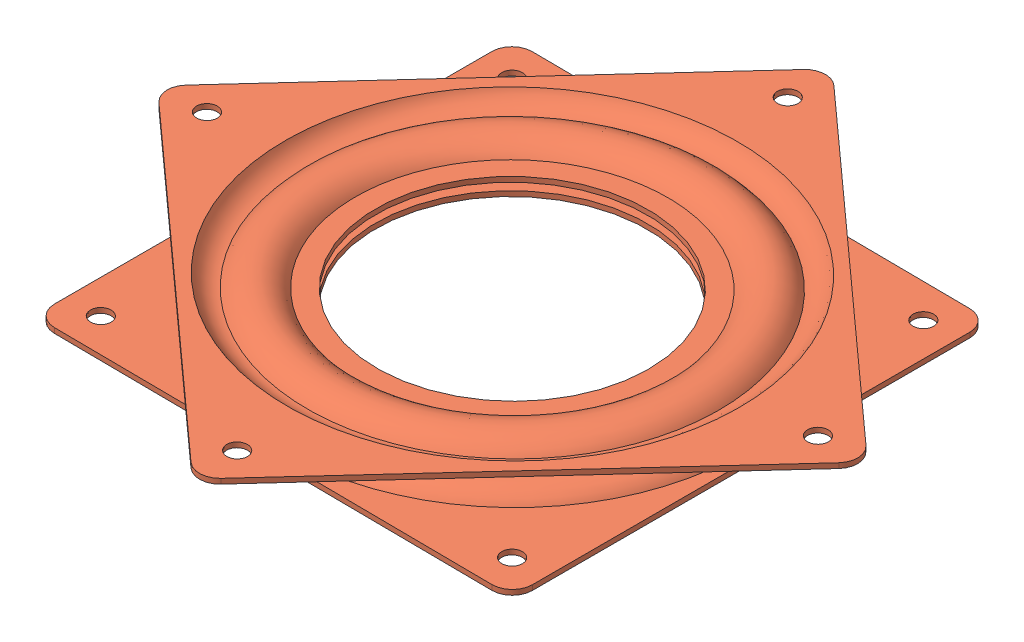
SolidWorks assembly 装配体1, configuration 默认. Lengths in mm.
Overall size (133.49 10.01 133.46).
32 component instances, 2 part files, 4 mates.
Components (placement in the parent):
- 6mmBearing-1: 6mmBearing [默认] at (34.5725 -23.9842 -78.8885) x (0.09369 0.188381 -0.977617) z (0.583167 0.785472 0.207244) size (6 6 6)
- HalfLazySusan-1: HalfLazySusan [默认] at (35.0426 -28.3053 -41.4748) x (-0.999962 0.008727 0) z (0 0 1) size (94.5 3.57 94.5)
- HalfLazySusan-2: HalfLazySusan [默认] at (35.1177 -19.7056 -41.4748) x (0.742856 -0.006483 0.669419) z (-0.669394 0.005842 0.742885) size (94.5 3.57 94.5)
- 6mmBearing-2: 6mmBearing [默认] at (42.067 -24.0496 -78.2035) x (0.09369 0.188381 -0.977617) z (0.583167 0.785472 0.207244) size (6 6 6)
- 6mmBearing-3: 6mmBearing [默认] at (49.2553 -24.1124 -75.9752) x (0.09369 0.188381 -0.977617) z (0.583167 0.785472 0.207244) size (6 6 6)
- 6mmBearing-4: 6mmBearing [默认] at (55.8233 -24.1697 -72.301) x (0.09369 0.188381 -0.977617) z (0.583167 0.785472 0.207244) size (6 6 6)
- 6mmBearing-5: 6mmBearing [默认] at (61.4839 -24.2191 -67.3414) x (0.09369 0.188381 -0.977617) z (0.583167 0.785472 0.207244) size (6 6 6)
- 6mmBearing-6: 6mmBearing [默认] at (65.9896 -24.2584 -61.3133) x (0.09369 0.188381 -0.977617) z (0.583167 0.785472 0.207244) size (6 6 6)
- 6mmBearing-7: 6mmBearing [默认] at (69.1437 -24.2859 -54.4801) x (0.09369 0.188381 -0.977617) z (0.583167 0.785472 0.207244) size (6 6 6)
- 6mmBearing-8: 6mmBearing [默认] at (70.8081 -24.3004 -47.1404) x (0.09369 0.188381 -0.977617) z (0.583167 0.785472 0.207244) size (6 6 6)
- 6mmBearing-9: 6mmBearing [默认] at (70.9103 -24.3013 -39.6151) x (0.09369 0.188381 -0.977617) z (0.583167 0.785472 0.207244) size (6 6 6)
- 6mmBearing-10: 6mmBearing [默认] at (69.4456 -24.2886 -32.2329) x (0.09369 0.188381 -0.977617) z (0.583167 0.785472 0.207244) size (6 6 6)
- 6mmBearing-11: 6mmBearing [默认] at (66.4782 -24.2627 -25.3166) x (0.09369 0.188381 -0.977617) z (0.583167 0.785472 0.207244) size (6 6 6)
- 6mmBearing-12: 6mmBearing [默认] at (62.1377 -24.2248 -19.1684) x (0.09369 0.188381 -0.977617) z (0.583167 0.785472 0.207244) size (6 6 6)
- 6mmBearing-13: 6mmBearing [默认] at (56.6138 -24.1766 -14.0571) x (0.09369 0.188381 -0.977617) z (0.583167 0.785472 0.207244) size (6 6 6)
- 6mmBearing-14: 6mmBearing [默认] at (50.148 -24.1201 -10.206) x (0.09369 0.188381 -0.977617) z (0.583167 0.785472 0.207244) size (6 6 6)
- 6mmBearing-15: 6mmBearing [默认] at (43.0228 -24.058 -7.7834) x (0.09369 0.188381 -0.977617) z (0.583167 0.785472 0.207244) size (6 6 6)
- 6mmBearing-16: 6mmBearing [默认] at (35.5496 -23.9927 -6.8952) x (0.09369 0.188381 -0.977617) z (0.583167 0.785472 0.207244) size (6 6 6)
- 6mmBearing-17: 6mmBearing [默认] at (28.0551 -23.9273 -7.5802) x (0.09369 0.188381 -0.977617) z (0.583167 0.785472 0.207244) size (6 6 6)
- 6mmBearing-18: 6mmBearing [默认] at (20.8668 -23.8646 -9.8085) x (0.09369 0.188381 -0.977617) z (0.583167 0.785472 0.207244) size (6 6 6)
- 6mmBearing-19: 6mmBearing [默认] at (14.2988 -23.8073 -13.4827) x (0.09369 0.188381 -0.977617) z (0.583167 0.785472 0.207244) size (6 6 6)
- 6mmBearing-20: 6mmBearing [默认] at (8.6382 -23.7579 -18.4423) x (0.09369 0.188381 -0.977617) z (0.583167 0.785472 0.207244) size (6 6 6)
- 6mmBearing-21: 6mmBearing [默认] at (4.1325 -23.7186 -24.4704) x (0.09369 0.188381 -0.977617) z (0.583167 0.785472 0.207244) size (6 6 6)
- 6mmBearing-22: 6mmBearing [默认] at (0.9785 -23.691 -31.3036) x (0.09369 0.188381 -0.977617) z (0.583167 0.785472 0.207244) size (6 6 6)
- 6mmBearing-23: 6mmBearing [默认] at (-0.686 -23.6765 -38.6432) x (0.09369 0.188381 -0.977617) z (0.583167 0.785472 0.207244) size (6 6 6)
- 6mmBearing-24: 6mmBearing [默认] at (-0.7881 -23.6756 -46.1686) x (0.09369 0.188381 -0.977617) z (0.583167 0.785472 0.207244) size (6 6 6)
- 6mmBearing-25: 6mmBearing [默认] at (0.6765 -23.6884 -53.5507) x (0.09369 0.188381 -0.977617) z (0.583167 0.785472 0.207244) size (6 6 6)
- 6mmBearing-26: 6mmBearing [默认] at (3.6439 -23.7143 -60.467) x (0.09369 0.188381 -0.977617) z (0.583167 0.785472 0.207244) size (6 6 6)
- 6mmBearing-27: 6mmBearing [默认] at (7.9844 -23.7522 -66.6152) x (0.09369 0.188381 -0.977617) z (0.583167 0.785472 0.207244) size (6 6 6)
- 6mmBearing-28: 6mmBearing [默认] at (13.5083 -23.8004 -71.7266) x (0.09369 0.188381 -0.977617) z (0.583167 0.785472 0.207244) size (6 6 6)
- 6mmBearing-29: 6mmBearing [默认] at (19.9741 -23.8568 -75.5777) x (0.09369 0.188381 -0.977617) z (0.583167 0.785472 0.207244) size (6 6 6)
- 6mmBearing-30: 6mmBearing [默认] at (27.0993 -23.919 -78.0003) x (0.09369 0.188381 -0.977617) z (0.583167 0.785472 0.207244) size (6 6 6)
Mates (geometry in assembly coordinates):
- 同心1: concentric anti-aligned: cylinder of HalfLazySusan-1 through (34.9823 -35.2222 -41.4748) axis (-0.008727 -0.999962 0) radius 27; cylinder of HalfLazySusan-2 through (35.178 -12.7887 -41.4748) axis (0.008727 0.999962 0) radius 27
- 距离1: distance = 8.6 mm anti-aligned: plane of HalfLazySusan-2 through (35.1177 -19.7056 -41.4748) normal (0.008727 0.999962 0); plane of HalfLazySusan-1 through (35.0426 -28.3053 -41.4748) normal (-0.008727 -0.999962 0)
- 相切4: tangent anti-aligned: torus of HalfLazySusan-2; sphere of 6mmBearing-13
- 相切5: tangent anti-aligned: edge_curve of HalfLazySusan-1; unknown of 6mmBearing-5
